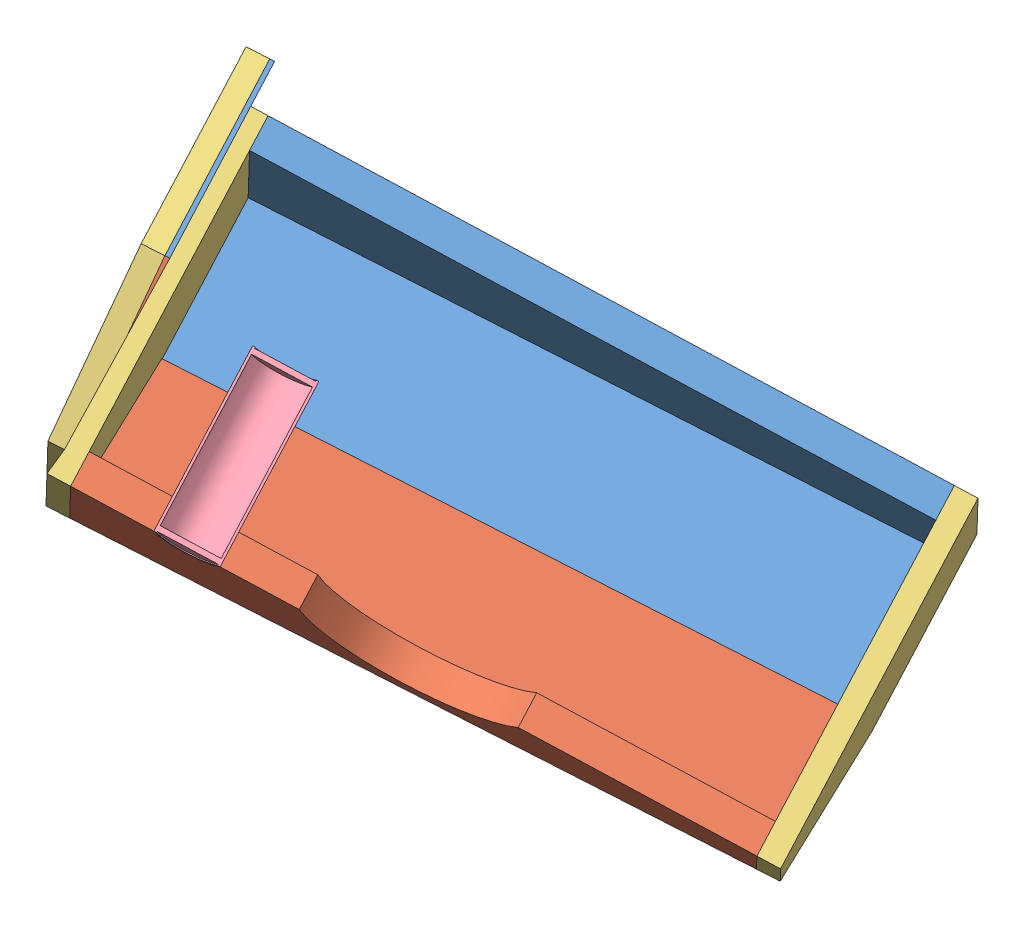
SolidWorks assembly woofer_solidw, configuration Défaut. Lengths in mm.
Overall size (713.51 690.31 689.58).
6 component instances, 5 part files, 10 mates.
Components (placement in the parent):
- back-2: back [Défaut] at (-192.8125 -0.0937 -170.4318) x (0.485611 0.732567 0.476999) z (0.863835 -0.318455 -0.390352) size (410 170 580)
- devant_tot-2: devant_tot [Défaut] at (-126.4543 -133.1022 84.9269) x (0.485611 0.732567 0.476999) z (0.863835 -0.318455 -0.390352) size (410 150 580)
- socle-2: socle [Défaut] at (374.5701 -317.8063 -141.4774) x (0.485611 0.732567 0.476999) z (0.863835 -0.318455 -0.390352) size (410 320 20)
- socle-3: socle [Défaut] at (-143.7311 -126.7331 92.7339) x (0.485611 0.732567 0.476999) z (0.863835 -0.318455 -0.390352) size (410 320 20)
- Pièce4^woofer_solidw-1: Pièce4^woofer_solidw [Défaut] at origin (virtual)
- tube-1: tube [Défaut] x (-0.450102 -0.744904 -0.492469) z (0.134056 -0.601608 0.787463) size (63 63 160)
Mates (geometry in assembly coordinates):
- Coïncidente6: coincident aligned: line of back-2 through (316.4331 -309.0482 -277.2774) axis (-0.863835 0.318455 0.390352); line of devant_tot-2 through (316.4331 -309.0482 -277.2774) axis (-0.863835 0.318455 0.390352)
- Coïncidente7: coincident aligned: plane of back-2 through (-192.8125 -0.0937 -170.4318) normal (-0.863835 0.318455 0.390352); plane of devant_tot-2 through (-126.4543 -133.1022 84.9269) normal (-0.863835 0.318455 0.390352)
- Coïncidente8: coincident anti-aligned: plane of back-2 through (308.2119 -184.7979 -396.836) normal (0.863835 -0.318455 -0.390352); plane of socle-2 through (374.5701 -317.8063 -141.4774) normal (-0.863835 0.318455 0.390352)
- Coïncidente9: coincident aligned: line of devant_tot-2 through (378.5918 -335.8546 -117.8535) axis (0.485611 0.732567 0.476999); line of socle-2 through (378.5918 -335.8546 -117.8535) axis (0.485611 0.732567 0.476999)
- Coïncidente10: coincident anti-aligned: line of back-2 through (492.7439 93.5776 -215.5765) axis (0.134056 -0.601608 0.787463); line of socle-2 through (515.5335 -8.6957 -81.7079) axis (-0.134056 0.601608 -0.787463)
- Coïncidente11: coincident aligned: line of back-2 through (-8.2805 278.2818 10.8278) axis (-0.485611 -0.732567 -0.476999); line of socle-3 through (-8.2805 278.2818 10.8278) axis (-0.485611 -0.732567 -0.476999)
- Coïncidente12: coincident aligned: line of back-2 through (-207.3808 -22.0707 -184.7417) axis (0.134056 -0.601608 0.787463); line of socle-3 through (-207.3808 -22.0707 -184.7417) axis (0.134056 -0.601608 0.787463)
- Coaxiale1: concentric anti-aligned: cylinder of devant_tot-2 through (1.3404 -6.0155 7.8738) axis (0.134056 -0.601608 0.787463) radius 31.5; cylinder of tube-1 through (21.449 -96.2572 125.994) axis (-0.134056 0.601608 -0.787463) radius 31.5
- Coïncidente14: coincident aligned: circle of devant_tot-2; circle of tube-1
- Coïncidente17: coincident: point of tube-1; point of assembly
